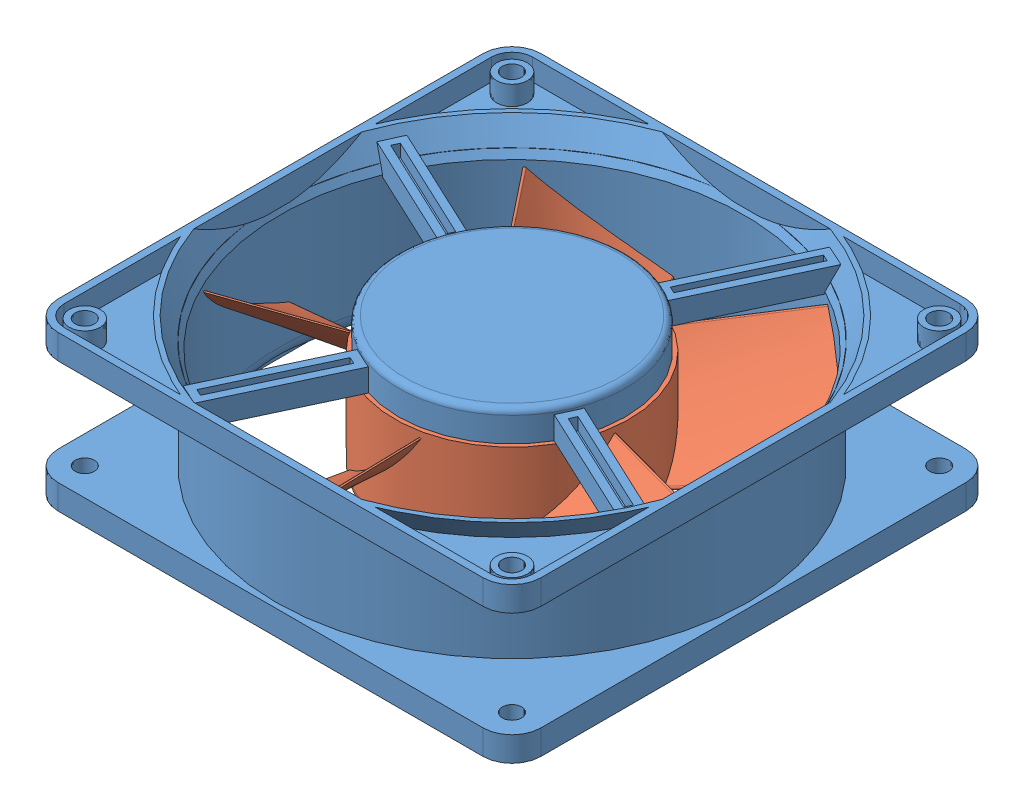
SolidWorks assembly fanlarge_ebmpabst_4212-12h, configuration Default. Lengths in mm.
Overall size (134.08 39.29 134.08).
2 component instances, 2 part files, 0 mates.
Components (placement in the parent):
- Fan Housing-11-1: Fan Housing-11 [Default] at origin size (118.87 39.29 118.87)
- fan-11-1: fan-11 [Default] at (-192.9031 11.4964 -8.5043) x (0.981481 0 0.19156) z (0 -1 0) size (114.3 114.3 26.42)
